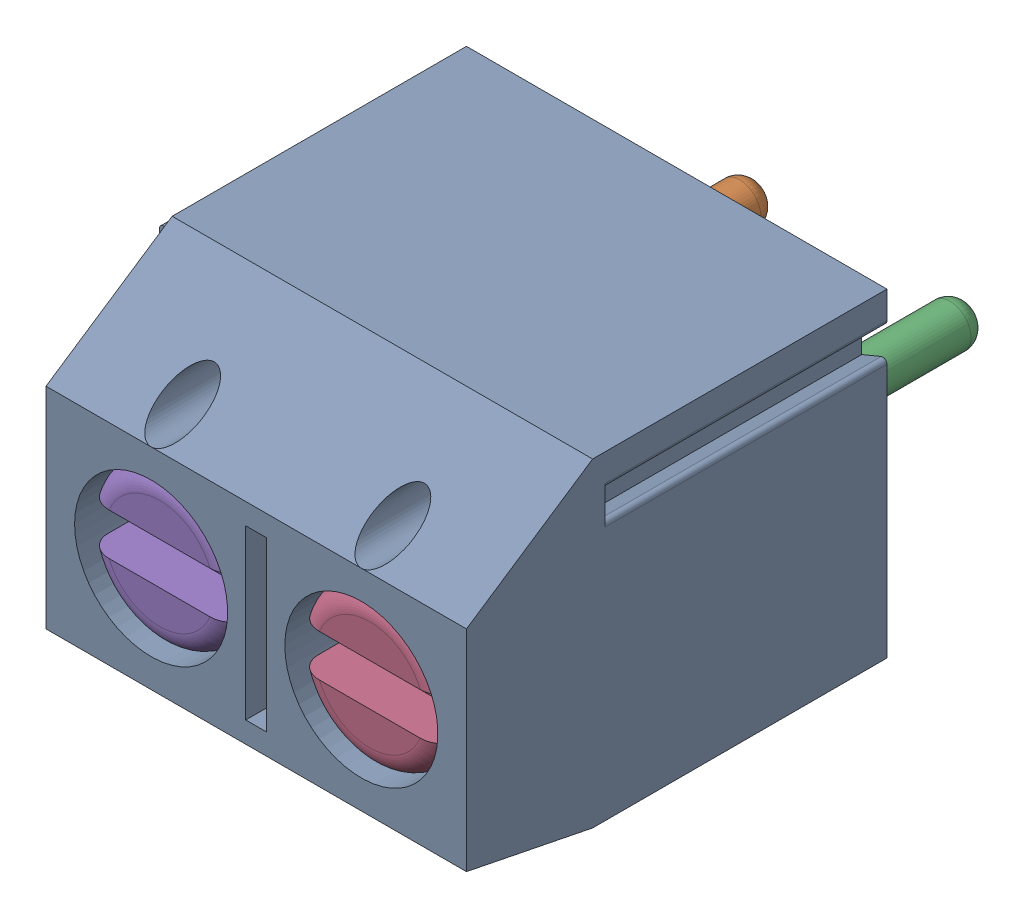
SolidWorks assembly DG301-5.0-02 (OPTION 1), configuration Default. Lengths in mm.
Overall size (10.6 7.6 14.4).
7 component instances, 4 part files, 0 mates.
Components (placement in the parent):
- DG301-5.0-02-body-1: DG301-5.0-02-body [Default] at origin size (10.6 7.6 10)
- DG301-5.0-pin-1: DG301-5.0-pin [Default] at (0 0.5 2.85) size (3.9 4 9.9)
- DG301-5.0-pin-2: DG301-5.0-pin [Default] at (5 0.5 2.85) size (3.9 4 9.9)
- DG301-5.0-screw-1: DG301-5.0-screw [Default] at (5 0 4) size (3.6 3.6 5.84)
- DG301-5.0-screw-2: DG301-5.0-screw [Default] at (0 0 4) size (3.6 3.6 5.84)
- DG301-5.0-wire_prot-1: DG301-5.0-wire_prot [Default] at (5 0 5.5) size (3.9 5.45 2.85)
- DG301-5.0-wire_prot-2: DG301-5.0-wire_prot [Default] at (0 0 5.5) size (3.9 5.45 2.85)
